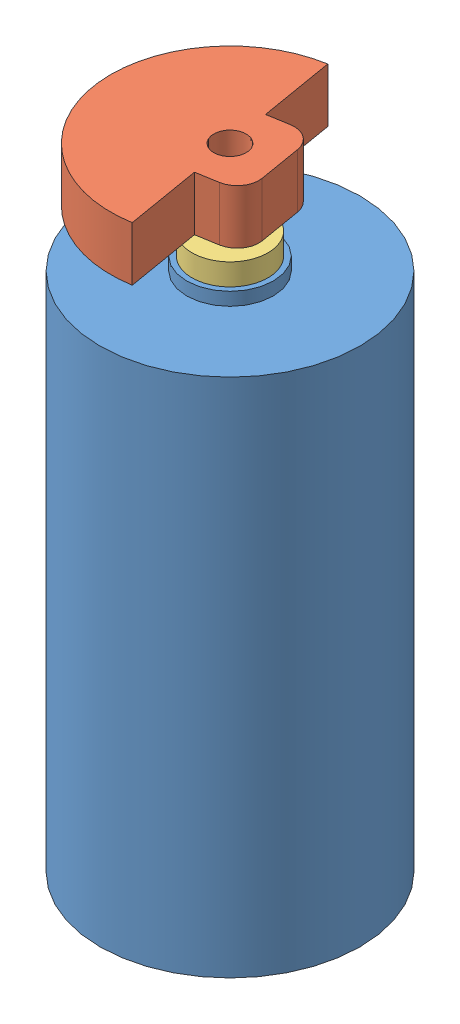
SolidWorks assembly vibration motor - assembly, configuration Default. Lengths in mm.
Overall size (6.17 14.55 6.17).
3 component instances, 3 part files, 4 mates.
Components (placement in the parent):
- vibration motor - body-1: vibration motor - body [Default] at (4.8436 -0.0036 9.4932) size (6 12.3 6)
- vibration motor - spinner-1: vibration motor - spinner [Default] at (4.8436 12.2964 9.4932) x (-0.166264 0 -0.986081) z (0.986081 0 -0.166264) size (5.5 2.25 3.75)
- vibration motor - washer-1: vibration motor - washer [Default] at (4.8436 12.7964 9.4932) x (-0.837169 0 -0.546944) z (-0.546944 0 0.837169) size (1.75 0.5 1.75)
Mates (geometry in assembly coordinates):
- Coincident1: coincident anti-aligned: plane of vibration motor - body-1 through (4.8436 12.2964 9.4932) normal (0 1 0); plane of vibration motor - washer-1 through (4.8436 12.2964 9.4932) normal (0 -1 0)
- Concentric1: concentric anti-aligned: cylinder of vibration motor - body-1 through (4.8436 12.2964 9.4932) axis (0 -1 0) radius 1; cylinder of vibration motor - washer-1 through (4.8436 12.2964 9.4932) axis (0 1 0) radius 0.875
- Coincident2: coincident anti-aligned: plane of vibration motor - body-1 through (4.8436 12.2964 9.4932) normal (0 1 0); plane of vibration motor - spinner-1 through (4.8436 12.2964 9.4932) normal (0 -1 0)
- Concentric3: concentric anti-aligned: cylinder of vibration motor - spinner-1 through (4.8436 13.2964 9.4932) axis (0 -1 0) radius 0.375; cylinder of vibration motor - washer-1 through (4.8436 12.2964 9.4932) axis (0 1 0) radius 0.375
